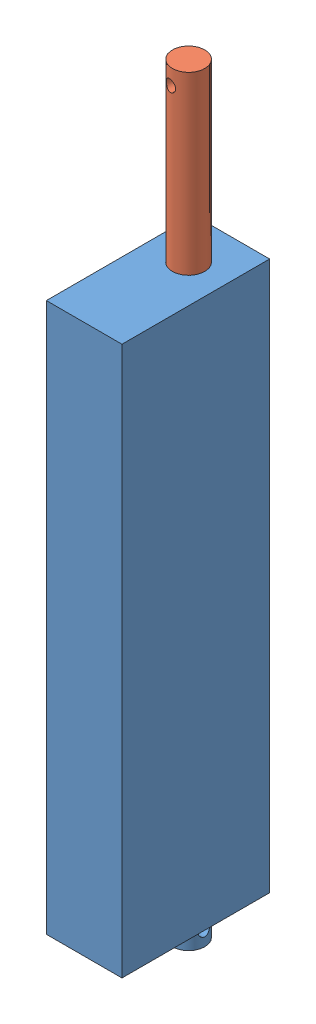
SolidWorks assembly Actuator, configuration Default. Lengths in mm.
Overall size (42.4 422.38 82.4).
2 component instances, 2 part files, 2 mates.
Components (placement in the parent):
- Actuator_Housing-1: Actuator_Housing [Default] at (-65.9416 28.6251 443.7918) size (42.4 325 82.4)
- Actuator_Rod-1: Actuator_Rod [Default] at (-44.9416 50.0091 385.7918) x (0.170764 0 -0.985312) z (0.985312 0 0.170764) size (19 381 19)
Mates (geometry in assembly coordinates):
- Concentric1: concentric anti-aligned: cylinder of Actuator_Housing-1 through (-44.9416 33.3876 385.7918) axis (0 1 0) radius 9.5; cylinder of Actuator_Rod-1 through (-44.9416 431.0091 385.7918) axis (0 -1 0) radius 9
- LimitDistance1: limit distance = 399.034 mm: cylinder of Actuator_Rod-1 through (-46.5639 422.0091 395.1522) axis (0.170764 0 -0.985312) radius 3.175; cylinder of Actuator_Housing-1 through (-65.9416 16.6251 385.7918) axis (1 0 0) radius 3.175
